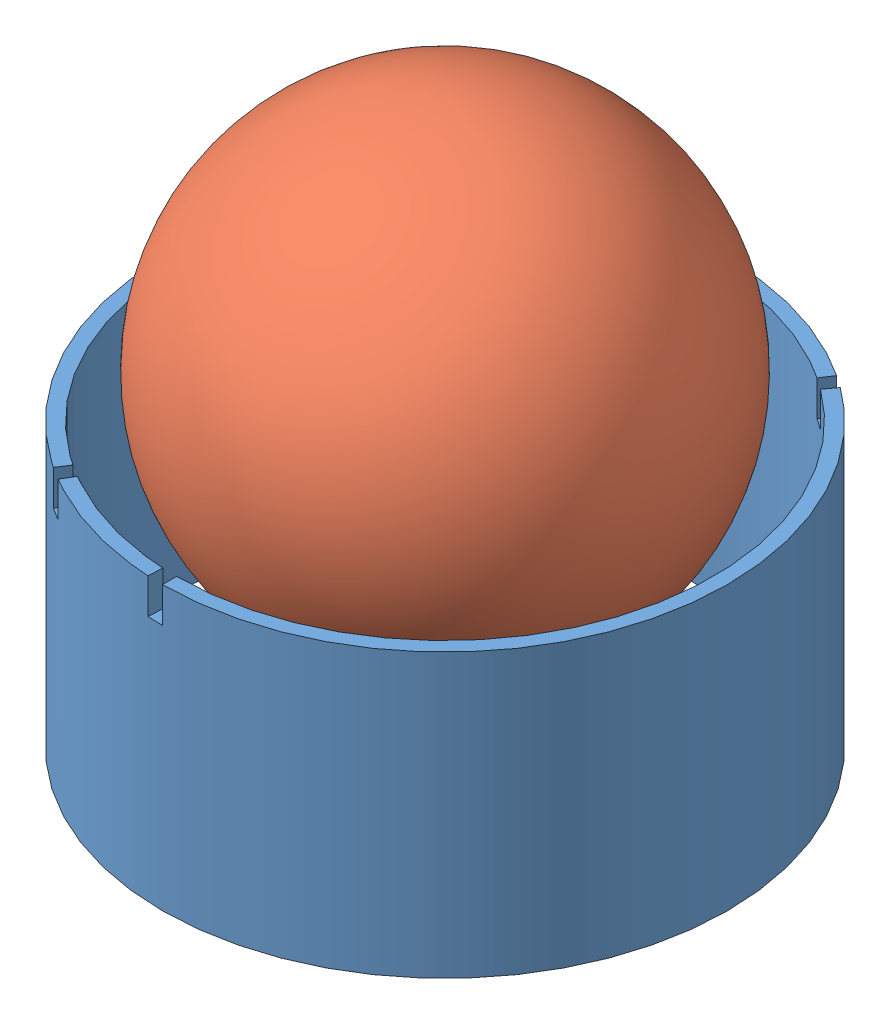
SolidWorks assembly Bougie_complete_Bleue, configuration Défaut. Lengths in mm.
Overall size (103.55 99.8 97.02).
2 component instances, 2 part files, 1 mates.
Components (placement in the parent):
- Bougie_Bleue-1: Bougie_Bleue [Défaut] at (-26.1532 -23.3286 0) size (80 50 80)
- Balle_Tennis_2-1: Balle_Tennis_2 [Défaut] at (-26.1532 22.9252 0) x (0.846755 0.314661 -0.428946) z (0.325561 0.331192 0.88562) size (65 65 65)
Mates (geometry in assembly coordinates):
- Coaxiale1: concentric: cylinder of Bougie_Bleue-1 through (-26.1532 26.6714 0) axis (0 -1 0) radius 36; sphere of Balle_Tennis_2-1
